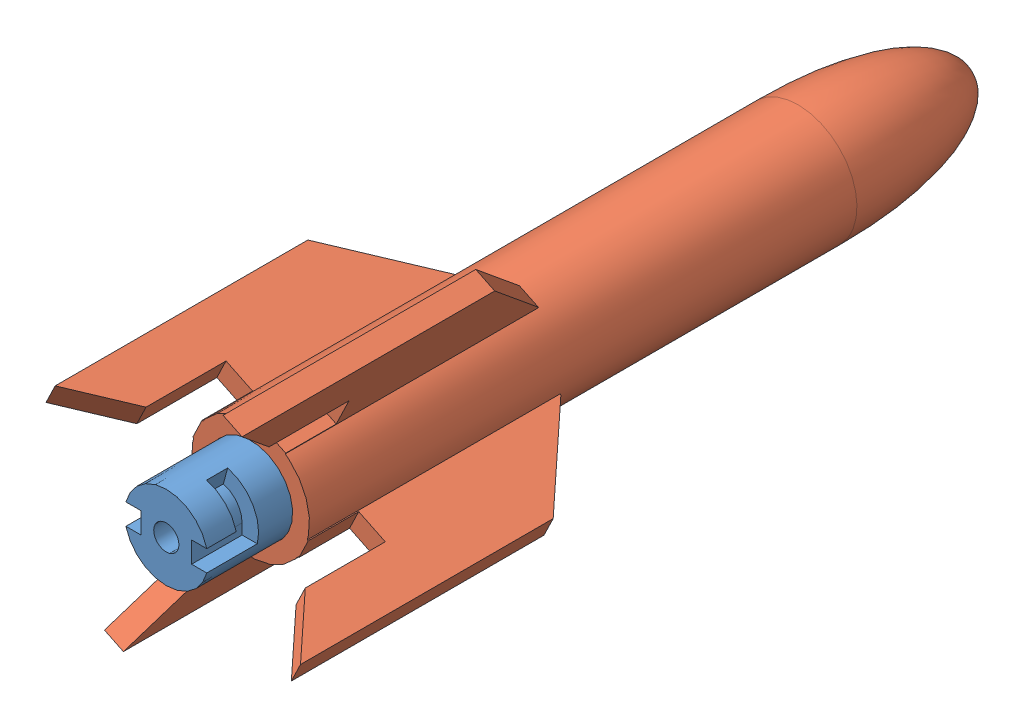
SolidWorks assembly Torpedo, configuration Default. Lengths in mm.
Overall size (54.88 54.88 120.71).
2 component instances, 2 part files, 6 mates.
Components (placement in the parent):
- Pressure Vessel-1: Pressure Vessel [Default] at (71.0407 89.3516 69.334) size (12.7 12.7 95.25)
- Shell-1: Shell [Default] at (71.0407 89.3516 151.884) x (-0.900265 0.435343 0) z (0 0 -1) size (41.09 41.09 119.67)
Mates (geometry in assembly coordinates):
- Concentric1: concentric anti-aligned: cylinder of Pressure Vessel-1 through (71.0407 89.3516 178.9524) axis (0 0 -1) radius 5.08; cylinder of 8063K210_AIR FILL VALVE-1 through (71.0407 89.3516 39.7815) axis (0 0 1) radius 1.9304
- Concentric2: concentric anti-aligned: cylinder of Pressure Vessel-1 through (71.0407 89.3516 178.9524) axis (0 0 -1) radius 5.08; cylinder of 8063K170_AIR FILL VALVE-1 through (71.0407 89.3516 55.0465) axis (0 0 1) radius 1.9304
- Concentric3: concentric anti-aligned: cylinder of Pressure Vessel-1 through (71.0407 89.3516 178.9524) axis (0 0 -1) radius 5.08; cylinder of 8063K170_AIR FILL VALVE-1 through (71.0407 89.3516 55.0465) axis (0 0 1) radius 1.9304
- Coincident1: coincident anti-aligned: plane of Pressure Vessel-1 through (71.0407 89.3516 69.334) normal (0 0 -1); plane of 8063K170_AIR FILL VALVE-1 through (71.0407 89.3516 69.334) normal (0 0 1)
- Concentric4: concentric anti-aligned: cylinder of Pressure Vessel-1 through (71.0407 89.3516 164.584) axis (0 0 -1) radius 6.35; cylinder of Shell-1 through (71.0407 89.3516 69.334) axis (0 0 1) radius 6.35
- Coincident2: coincident aligned: plane of Pressure Vessel-1 through (71.0407 89.3516 69.334) normal (0 0 -1); circle of Shell-1
